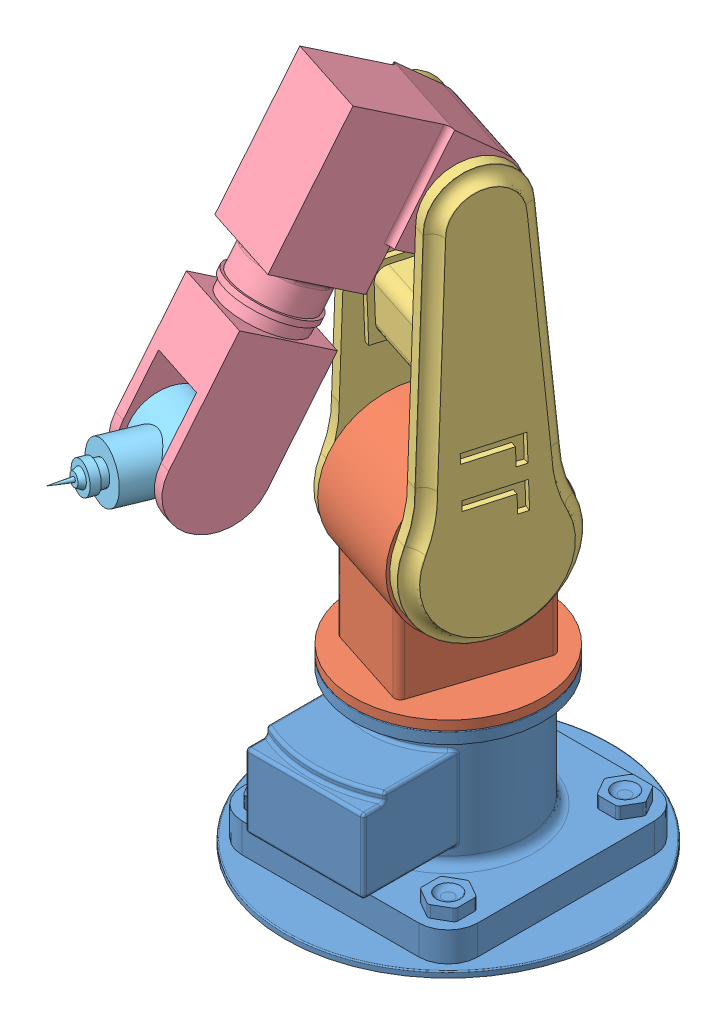
SolidWorks assembly Robot_arm_project, configuration Default. Lengths in mm.
Overall size (555 1182.12 811.42).
5 component instances, 5 part files, 8 mates.
Components (placement in the parent):
- Final Project Part 1-1: Final Project Part 1 [Default] at (174.1673 49.2569 511.6149) size (555 280 555)
- Final Project Part 2-1: Final Project Part 2 [Default] at (174.1673 209.2569 511.6149) x (0.308037 0 -0.951374) z (0.951374 0 0.308037) size (320 466 320)
- Final Project Part 3-1: Final Project Part 3 [Default] at (174.1673 545.2569 511.6149) x (0.307898 0.030045 -0.950945) z (0.009255 -0.999549 -0.028584) size (250 260.14 700)
- Final Project Part 4-1: Final Project Part 4 [Default] at (143.9016 1195.5706 605.0907) x (-0.147053 -0.878694 0.454173) z (-0.951374 0 -0.308037) size (595 297.5 160)
- Final Project Part 5-1: Final Project Part 5 [Default] at (67.4343 738.6499 841.2606) x (-0.307489 0.059601 0.949683) z (-0.951374 0 -0.308037) size (275 130 100)
Mates (geometry in assembly coordinates):
- Concentric1: concentric anti-aligned: cylinder of Final Project Part 1-1 through (174.1673 129.2569 511.6149) axis (0 1 0) radius 100; cylinder of Final Project Part 2-1 through (174.1673 329.2569 511.6149) axis (0 -1 0) radius 100
- Coincident1: coincident anti-aligned: plane of Final Project Part 1-1 through (174.1673 329.2569 511.6149) normal (0 1 0); plane of Final Project Part 2-1 through (174.1673 329.2569 511.6149) normal (0 -1 0)
- Concentric2: concentric aligned: cylinder of Final Project Part 2-1 through (259.791 545.2569 539.3382) axis (-0.951374 0 -0.308037) radius 75; cylinder of Final Project Part 3-1 through (259.791 545.2569 539.3382) axis (-0.951374 0 -0.308037) radius 75
- Coincident2: coincident anti-aligned: plane of Final Project Part 2-1 through (259.791 545.2569 539.3382) normal (0.951374 0 0.308037); plane of Final Project Part 3-1 through (259.791 545.2569 539.3382) normal (-0.951374 0 -0.308037)
- Concentric3: concentric anti-aligned: cylinder of Final Project Part 3-1 through (255.1635 1045.0311 553.6302) axis (-0.951374 0 -0.308037) radius 50; cylinder of Final Project Part 4-1 through (93.4299 1045.0311 501.2639) axis (0.951374 0 0.308037) radius 50
- Width1: width anti-aligned: plane of Final Project Part 3-1 through (88.5436 545.2569 483.8915) normal (0.951374 0 0.308037); plane of Final Project Part 4-1 through (259.791 545.2569 539.3382) normal (-0.951374 0 -0.308037); plane of Final Project Part 3-1 through (93.4299 1045.0311 501.2639) normal (-0.951374 0 -0.308037); plane of Final Project Part 4-1 through (245.6498 1045.0311 550.5498) normal (0.951374 0 0.308037)
- Concentric4: concentric aligned: cylinder of Final Project Part 4-1 through (19.8656 738.6499 825.8588) axis (0.951374 0 0.308037) radius 50; cylinder of Final Project Part 5-1 through (19.8656 738.6499 825.8588) axis (0.951374 0 0.308037) radius 50
- Width2: width anti-aligned: plane of Final Project Part 4-1 through (19.8656 738.6499 825.8588) normal (0.951374 0 0.308037); plane of Final Project Part 5-1 through (115.003 738.6499 856.6624) normal (-0.951374 0 -0.308037); plane of Final Project Part 4-1 through (19.8656 738.6499 825.8588) normal (-0.951374 0 -0.308037); plane of Final Project Part 5-1 through (115.003 738.6499 856.6624) normal (0.951374 0 0.308037)
